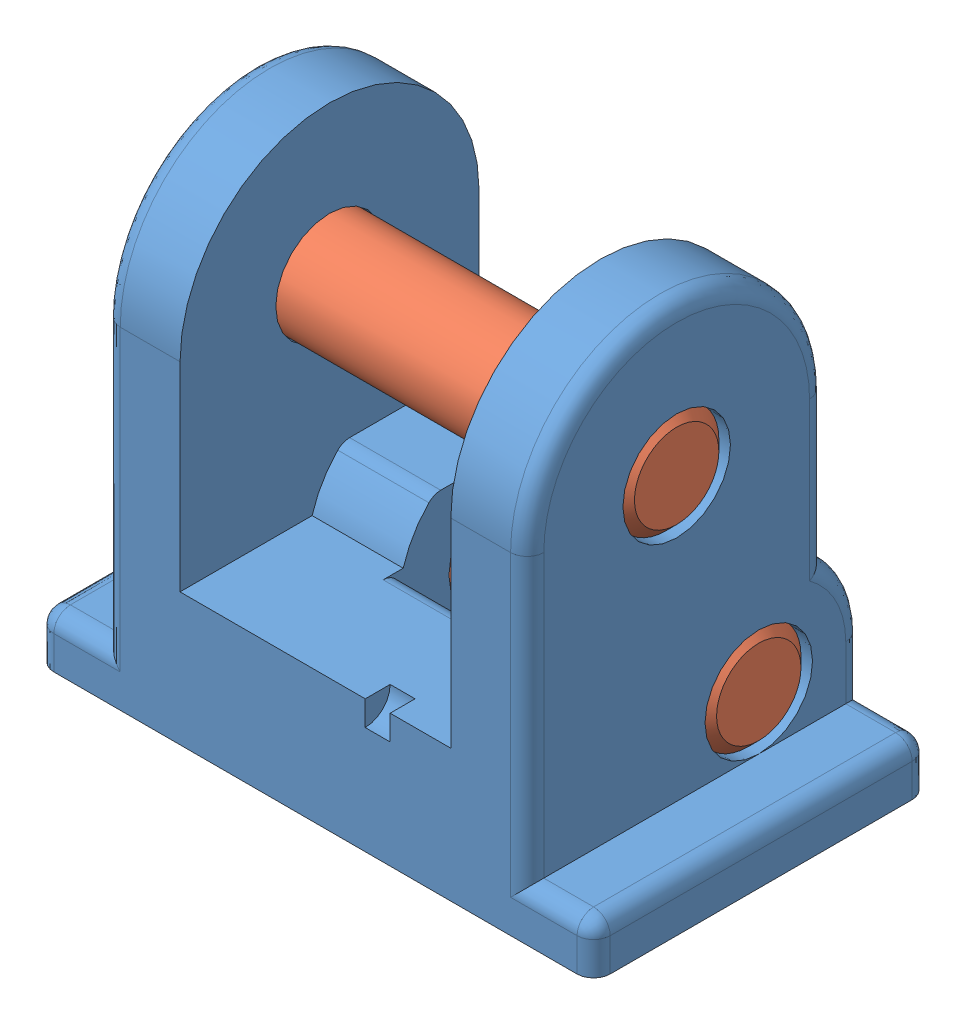
SolidWorks assembly finger_base_pf, configuration Default. Lengths in mm.
Overall size (33.5 28.98 20.18).
3 component instances, 2 part files, 4 mates.
Components (placement in the parent):
- pivot_base-1: pivot_base [Default] at (29.9046 41.615 134.046) x (-1 0 0) z (0 0 -1) size (33.5 28.98 20.18)
- 98381A542 D1-4 L1-1: 98381A542 D1-4 L1 [98381A542] at (29.9546 61.59 138.9886) size (25.4 6.35 6.35)
- 98381A542 D1-4 L1-2: 98381A542 D1-4 L1 [98381A542] at (29.9546 47.8525 134.046) size (25.4 6.35 6.35)
Mates (geometry in assembly coordinates):
- Concentric4: concentric: circle of pivot_base-1; circle of 98381A542 D1-4 L1-1
- Coincident4: coincident: plane of pivot_base-1 through (42.6546 47.8525 134.046) normal (1 0 0); plane of 98381A542 D1-4 L1-1 through (42.6546 61.59 138.9886) normal (1 0 0)
- Concentric5: concentric: cylinder of pivot_base-1 through (17.1546 47.8525 134.046) axis (1 0 0) radius 3.2375; circle of 98381A542 D1-4 L1-2
- Coincident5: coincident: plane of pivot_base-1 through (42.6546 47.8525 134.046) normal (1 0 0); plane of 98381A542 D1-4 L1-2 through (42.6546 47.8525 134.046) normal (1 0 0)
